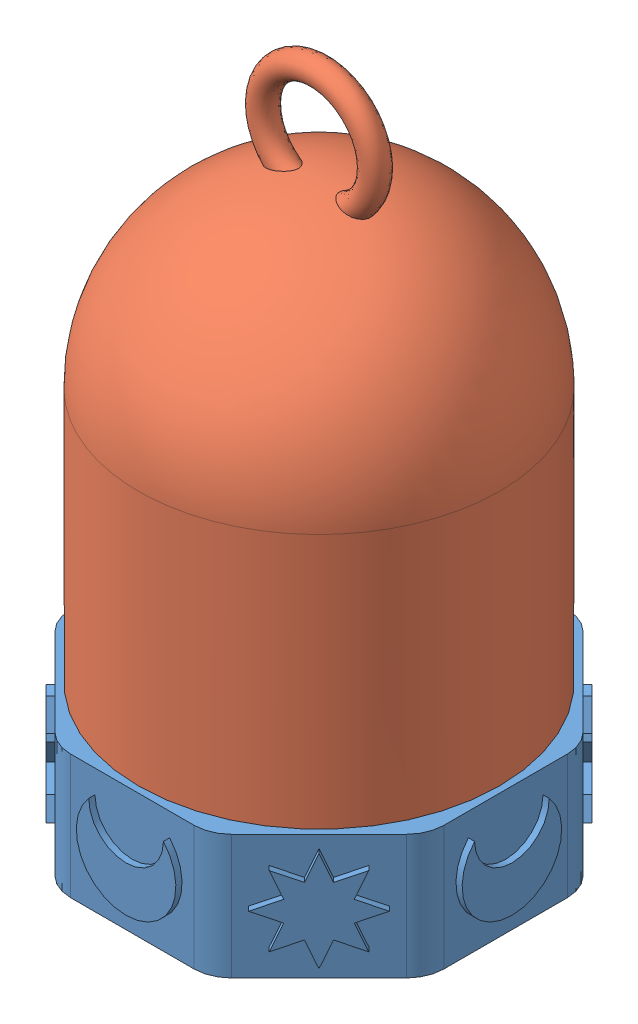
SolidWorks assembly Chevalier_Taylor_Flower Pod Whole, configuration Default. Lengths in mm.
Overall size (78.74 135.89 78.74).
3 component instances, 3 part files, 7 mates.
Components (placement in the parent):
- Chevalier_Taylor_Flower Pod Base-1: Chevalier_Taylor_Flower Pod Base [Default] at origin size (78.74 34.97 78.74)
- Chevalier_Taylor_Flower Pod Dome-1: Chevalier_Taylor_Flower Pod Dome [Default] at (0 25.4 0) size (73.66 110.49 74.78)
- Chevalier_Taylor_Flower-2: Chevalier_Taylor_Flower [Default] at (0 2.54 0) size (33.03 36.94 33.03)
Mates (geometry in assembly coordinates):
- Coincident2: coordinate: point of Flower Pod Base-1
- Concentric1: concentric anti-aligned: circle of Flower Pod Base-1; circle of Flower-2
- Coincident4: coincident anti-aligned: plane of Chevalier_Taylor_Flower Pod Base-1 through (0 2.54 0) normal (0 1 0); plane of Chevalier_Taylor_Flower-2 through (0 2.54 0) normal (0 -1 0)
- Concentric2: concentric aligned: cylinder of Chevalier_Taylor_Flower Pod Base-1 through (0 34.29 0) axis (0 -1 0) radius 31.75; cylinder of Flower Pod Dome-1 through (0 25.4 0) axis (0 -1 0) radius 35.56
- Coincident6: coincident anti-aligned: plane of Chevalier_Taylor_Flower Pod Base-1 through (0 25.4 0) normal (0 1 0); plane of Flower Pod Dome-1 through (0 25.4 0) normal (0 -1 0)
- Coincident7: coincident aligned: plane of Flower Pod Dome-1 through (0 25.4 0) normal (0 0 1)
- Coincident8: coincident aligned: plane of Chevalier_Taylor_Flower-2 through (0 2.54 0) normal (0 0 1)
